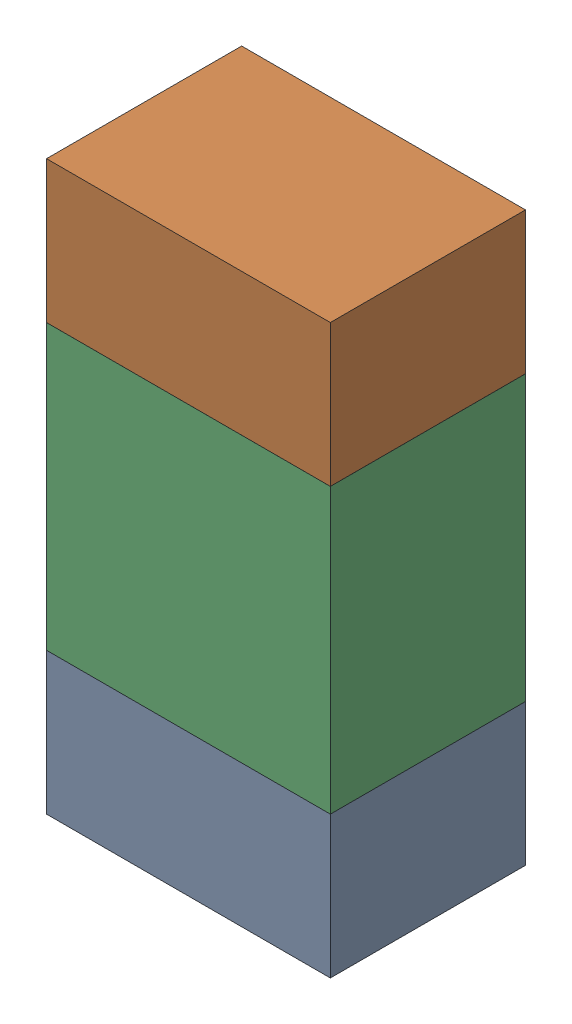
SolidWorks assembly R6, configuration ﾃﾞﾌｫﾙﾄ. Lengths in mm.
Overall size (0.8 1.6 0.55).
6 component instances, 2 part files, 0 mates.
Components (placement in the parent):
- 689261784-1: 689261784 [ﾃﾞﾌｫﾙﾄ] at (13.4999 24.1501 0) size (0.8 0.4 0.55)
  - Extruded_34-1: Extruded_34 [ﾃﾞﾌｫﾙﾄ] at origin size (0.8 0.4 0.55)
- 689261784-2: 689261784 [ﾃﾞﾌｫﾙﾄ] at (13.4999 25.3501 0) size (0.8 0.4 0.55)
  - Extruded_34-1: Extruded_34 [ﾃﾞﾌｫﾙﾄ] at origin size (0.8 0.4 0.55)
- 689261648-1: 689261648 [ﾃﾞﾌｫﾙﾄ] at (13.4999 24.75 0) size (0.8 0.8 0.55)
  - Extruded_33-1: Extruded_33 [ﾃﾞﾌｫﾙﾄ] at origin size (0.8 0.8 0.55)
